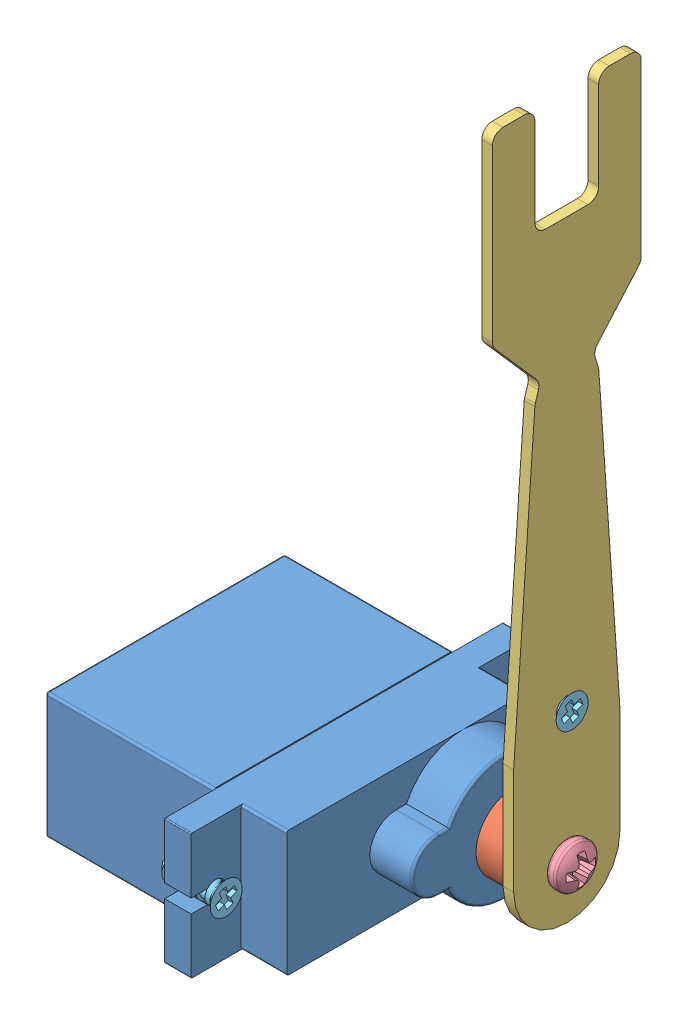
SolidWorks assembly AR2, configuration Predeterminado. Lengths in mm.
Overall size (34.06 68.75 31.9).
7 component instances, 5 part files, 28 mates.
Components (placement in the parent):
- sg90-1: sg90 [Default] at (175.3764 -204.8635 98.9775) x (0 0 1) z (0 1 0) size (31.9 29.9 11.8)
- SG90 plastic Horn-1: SG90 plastic Horn [Default] at (204.8264 -198.9635 104.8775) x (0 0.999858 0.016879) z (0 0.016879 -0.999858) size (19.4 4 7.07)
- Arm-1: Arm [Predeterminado] at (207.8264 -183.2019 150.0835) x (0 0 -1) z (1 0 0) size (14 67.85 1)
- (M2_3_mm)_90116A007_METRIC 316 SS PAN HEAD PHILLIPS MACHINE SCREW-1: (M2_3_mm)_90116A007_METRIC 316 SS PAN HEAD PHILLIPS MACHINE SCREW [90116A007] at (204.8264 -198.9635 104.8775) x (0 0 -1) z (1 0 0) size (4 4 4.68)
- M2x6 SelfTap Screw-2: M2x6 SelfTap Screw [Predeterminado] at (208.3264 -186.4635 104.8775) x (0 -0.924225 -0.381849) z (1 0 0) size (3.4 3.28 6)
- M2x6 SelfTap Screw-4: M2x6 SelfTap Screw [Predeterminado] at (194.7764 -198.9635 123.8775) x (0 -0.924225 -0.381849) z (1 0 0) size (3.4 3.28 6)
- M2x6 SelfTap Screw-6: M2x6 SelfTap Screw [Predeterminado] at (194.7764 -198.9635 96.5775) x (0 -0.924225 -0.381849) z (1 0 0) size (3.4 3.28 6)
Mates (geometry in assembly coordinates):
- Coincidente272: coincident: plane of sg90-1 through (205.2764 -198.9635 104.8775) normal (1 0 0); plane of SG90 plastic Horn-1 through (205.2764 -197.7187 104.8985) normal (-1 0 0)
- Concéntrica139: concentric: circle of sg90-1; circle of SG90 plastic Horn-1
- Concéntrica154: concentric: circle of sg90-1; circle of M2x6 SelfTap Screw-6
- Distancia47: distance = 1 mm: plane of M2x6 SelfTap Screw-6 through (194.7764 -198.9635 96.5775) normal (1 0 0); plane of sg90-1 through (193.7764 -204.8635 94.2775) normal (1 0 0)
- Concéntrica155: concentric: circle of sg90-1; circle of M2x6 SelfTap Screw-4
- Distancia48: distance = 1 mm: plane of M2x6 SelfTap Screw-4 through (194.7764 -198.9635 123.8775) normal (1 0 0); plane of sg90-1 through (193.7764 -193.0635 126.1775) normal (1 0 0)
- Coincidente273: coincident: plane of ? through (96.918 -198.9635 104.8775) normal (-1 0 0); plane of ? through (96.918 -197.7188 104.9044) normal (1 0 0)
- Concéntrica140: concentric: circle of ?; circle of ?
- Concéntrica156: concentric: circle of ?; circle of ?
- Distancia49: distance = 1 mm: plane of ? through (107.418 -198.9635 96.5775) normal (-1 0 0); plane of ? through (108.418 -193.0635 94.2775) normal (-1 0 0)
- Concéntrica158: concentric: circle of ?; circle of ?
- Distancia50: distance = 1 mm: plane of ? through (107.418 -198.9635 123.8775) normal (-1 0 0); plane of ? through (108.418 -204.8635 126.1775) normal (-1 0 0)
- Coincidente275: coincident: plane of SG90 plastic Horn-1 through (206.8264 -195.429 104.9372) normal (1 0 0); plane of Arm-1 through (206.8264 -158.9009 101.2558) normal (-1 0 0)
- Concéntrica143: concentric: circle of SG90 plastic Horn-1; circle of Arm-1
- Bloquear1: lock: unknown of SG90 plastic Horn-1; unknown of Arm-1
- Coincidente278: coincident: plane of ? through (95.368 -195.4293 104.9539) normal (-1 0 0); plane of ? through (95.368 -158.9009 108.4991) normal (1 0 0)
- Concéntrica144: concentric: circle of ?; circle of ?
- Bloquear2: lock: unknown of ?; unknown of ?
- Bloquear3: lock: unknown of ?; unknown of ?
- Bloquear4: lock: unknown of ?; unknown of ?
- Coincidente281: coincident: plane of Arm-1 through (207.8264 -158.9009 101.2558) normal (1 0 0); plane of (M2_3_mm)_90116A007_METRIC 316 SS PAN HEAD PHILLIPS MACHINE SCREW-1 through (207.8264 -198.9635 104.8775) normal (-1 0 0)
- Concéntrica145: concentric: circle of Arm-1; circle of (M2_3_mm)_90116A007_METRIC 316 SS PAN HEAD PHILLIPS MACHINE SCREW-1
- Concéntrica148: concentric: circle of Arm-1; circle of M2x6 SelfTap Screw-2
- Distancia46: distance = 0.5 mm: plane of M2x6 SelfTap Screw-2 through (208.3264 -186.4635 104.8775) normal (1 0 0); plane of Arm-1 through (207.8264 -158.9009 101.2558) normal (1 0 0)
- Coincidente282: coincident: plane of ? through (94.368 -158.9009 108.4991) normal (-1 0 0); plane of ? through (94.368 -198.9635 104.8775) normal (1 0 0)
- Concéntrica146: concentric: circle of ?; circle of ?
- Concéntrica147: concentric: circle of ?; circle of ?
- Distancia45: distance = 0.5 mm: plane of ? through (93.868 -186.4635 104.8775) normal (-1 0 0); plane of ? through (94.368 -158.9009 108.4991) normal (-1 0 0)
